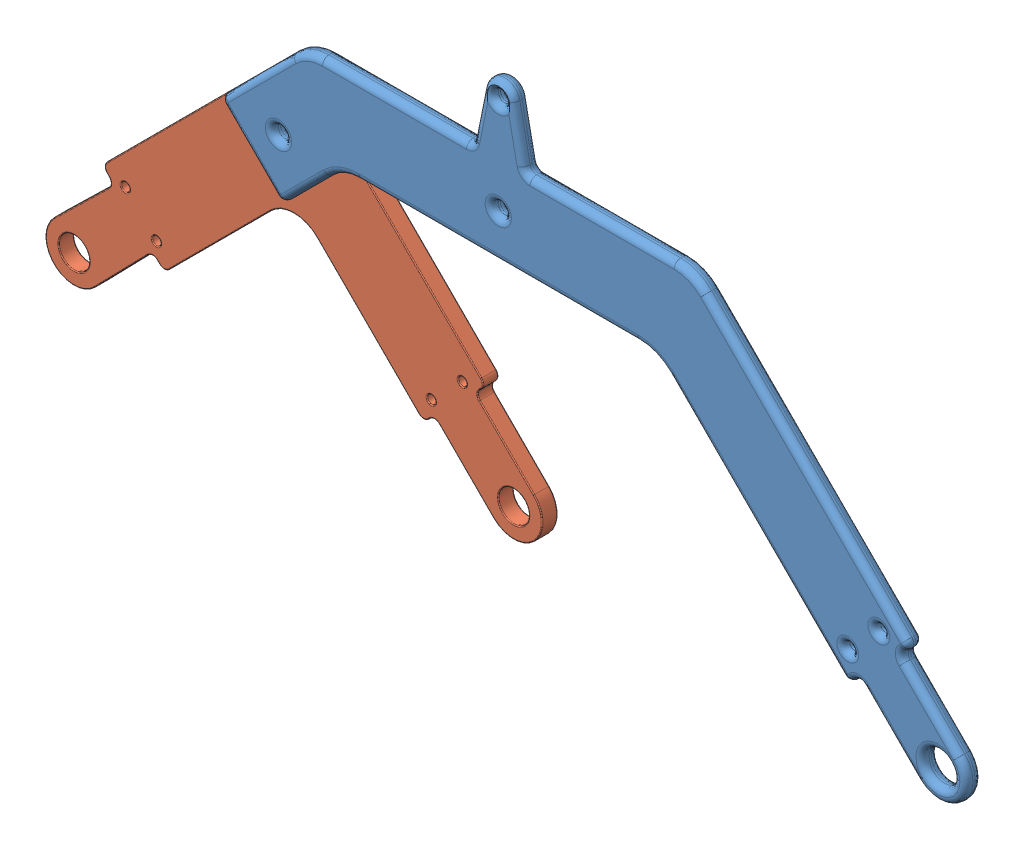
SolidWorks assembly Right Rocker Bogie, configuration Default. Lengths in mm.
Overall size (213 92 7.33).
2 component instances, 2 part files, 2 mates.
Components (placement in the parent):
- rocker-1: rocker [Default] at (10.6746 78.5183 71.9057) size (169.47 92 4.16)
- Bogie-1: Bogie [Default] at (10.6746 78.5183 68.4057) size (113 67.54 3.5)
Mates (geometry in assembly coordinates):
- Concentric1: concentric anti-aligned: cylinder of rocker-1 through (-39.3254 128.5183 75.4057) axis (0 0 -1) radius 1.5; circle of Bogie-1
- Coincident1: coincident anti-aligned: plane of rocker-1 through (110.6746 78.5183 71.9057) normal (0 0 -1); plane of Bogie-1 through (10.6746 78.5183 71.9057) normal (0 0 1)
